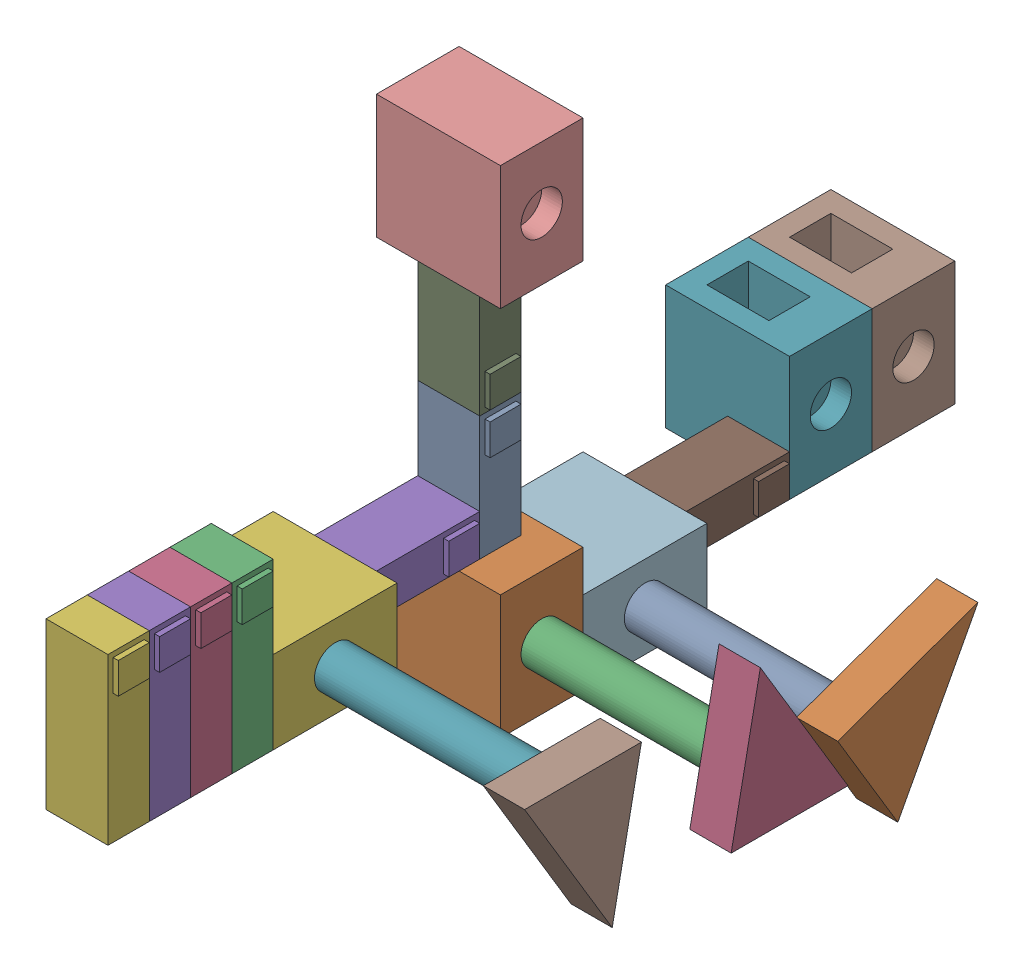
SolidWorks assembly Assem3, configuration Default. Lengths in mm.
Overall size (254 353.32 546.1).
27 component instances, 4 part files, 39 mates.
Components (placement in the parent):
- Assem1-1: Assem1 [Default] at origin size (76.2 152.4 50.8)
  - Part1-1: Part1 [Default] at (12.7 50.8 -12.7) size (41.27 101.6 25.4)
  - Part2-1: Part2 [Default] at origin size (76.2 76.2 50.8)
- Assem2-1: Assem2 [Default] at (228.6 20.1395 -61.321) x (0 0 1) z (0 -1 0) size (125.72 165.1 125.72)
  - Part3-1: Part3 [Default] at (35.921 12.7 -17.9605) x (0.684961 0 -0.72858) z (0.72858 0 0.684961) size (25.4 152.4 25.4)
  - Part4-1: Part4 [Default] x (0.707107 0 -0.707107) z (0.707107 0 0.707107) size (101.6 25.4 76.2)
- Assem1-2: Assem1 [Default] at (0 114.3 139.7) x (1 0 0) z (0 1 0) size (76.2 152.4 50.8)
  - Part1-1: Part1 [Default] at (12.7 50.8 -12.7) size (41.27 101.6 25.4)
  - Part2-1: Part2 [Default] at origin size (76.2 76.2 50.8)
- Assem2-2: Assem2 [Default] at (228.6 106.8605 137.521) x (0 0 -1) z (0 1 0) size (125.72 165.1 125.72)
  - Part3-1: Part3 [Default] at (35.921 12.7 -17.9605) x (0.684961 0 -0.72858) z (0.72858 0 0.684961) size (25.4 152.4 25.4)
  - Part4-1: Part4 [Default] x (0.707107 0 -0.707107) z (0.707107 0 0.707107) size (101.6 25.4 76.2)
- Assem1-3: Assem1 [Default] at (0 304.8 -50.8) x (1 0 0) z (0 0 -1) size (76.2 152.4 50.8)
  - Part1-1: Part1 [Default] at (12.7 50.8 -12.7) size (41.27 101.6 25.4)
  - Part2-1: Part2 [Default] at origin size (76.2 76.2 50.8)
- Assem1-4: Assem1 [Default] at (0 50.8 -50.8) x (1 0 0) z (0 1 0) size (76.2 152.4 50.8)
  - Part1-1: Part1 [Default] at (12.7 50.8 -12.7) size (41.27 101.6 25.4)
  - Part2-1: Part2 [Default] at origin size (76.2 76.2 50.8)
- Assem2-3: Assem2 [Default] at (228.6 -14.6426 -91.9802) x (0 0.857493 0.514496) z (0 -0.514496 0.857493) size (125.72 165.1 125.72)
  - Part3-1: Part3 [Default] at (35.921 12.7 -17.9605) x (0.684961 0 -0.72858) z (0.72858 0 0.684961) size (25.4 152.4 25.4)
  - Part4-1: Part4 [Default] x (0.707107 0 -0.707107) z (0.707107 0 0.707107) size (101.6 25.4 76.2)
- Part1-1: Part1 [Default] at (38.1 63.5 165.1) size (41.27 101.6 25.4)
- Part1-2: Part1 [Default] at (38.1 63.5 190.5) size (41.27 101.6 25.4)
- Part1-3: Part1 [Default] at (38.1 63.5 215.9) size (41.27 101.6 25.4)
- Part1-4: Part1 [Default] at (38.1 63.5 241.3) size (41.27 101.6 25.4)
- Part2-1: Part2 [Default] at (-25.4 12.7 -203.2) size (76.2 76.2 50.8)
- Part2-2: Part2 [Default] at (-25.4 12.7 -254) size (76.2 76.2 50.8)
Mates (geometry in assembly coordinates):
- Coincident1: coincident anti-aligned: plane of Assem1-1/Part2-1 through (63.5 38.1 -25.4) normal (1 0 0); plane of Assem2-1/Part3-1 through (63.5 38.1 -25.4) normal (-1 0 0)
- Concentric1: concentric aligned: cylinder of Assem1-1/Part2-1 through (63.5 38.1 -25.4) axis (1 0 0) radius 12.7; cylinder of Assem2-1/Part3-1 through (63.5 38.1 -25.4) axis (1 0 0) radius 12.7
- Coincident2: coincident: point of Assem1-1/Part2-1
- Coincident4: coincident aligned: plane of Assem1-1 through (0 0 0) normal (0 1 0)
- Parallel1: parallel anti-aligned: plane of Assem2-1 through (228.6 20.1395 -61.321) normal (0 -1 0)
- Coincident6: coincident aligned: plane of Assem1-1 through (0 0 0) normal (0 0 1)
- Coincident7: coincident aligned: plane of Assem1-1/Part1-1 through (50.8 152.4 -12.7) normal (1 0 0); plane of Assem1-2/Part1-1 through (50.8 101.6 -12.7) normal (1 0 0)
- Coincident8: coincident anti-aligned: plane of Assem1-1/Part1-1 through (12.7 152.4 -12.7) normal (0 0 1); plane of Assem1-2/Part1-1 through (12.7 101.6 -12.7) normal (0 0 -1)
- Coincident9: coincident anti-aligned: plane of Assem1-1/Part2-1 through (0 76.2 0) normal (0 1 0); plane of Assem1-2/Part1-1 through (12.7 76.2 -12.7) normal (0 -1 0)
- Concentric2: concentric aligned: cylinder of Assem1-2/Part2-1 through (63.5 88.9 101.6) axis (1 0 0) radius 12.7; cylinder of Assem2-2/Part3-1 through (63.5 88.9 101.6) axis (1 0 0) radius 12.7
- Coincident10: coincident anti-aligned: plane of Assem1-2/Part2-1 through (63.5 88.9 101.6) normal (1 0 0); plane of Assem2-2/Part3-1 through (63.5 88.9 101.6) normal (-1 0 0)
- Parallel2: parallel anti-aligned: plane of Assem2-1/Part4-1 through (203.2 20.1395 10.521) normal (0 0.196116 0.980581); plane of Assem2-2/Part4-1 through (203.2 106.8605 65.679) normal (0 -0.196116 -0.980581)
- Coincident11: coincident anti-aligned: plane of Assem1-1/Part1-1 through (12.7 152.4 -12.7) normal (0 1 0); plane of Assem1-3/Part1-1 through (12.7 152.4 -38.1) normal (0 -1 0)
- Coincident12: coincident aligned: plane of Assem1-1/Part1-1 through (12.7 152.4 -12.7) normal (-1 0 0); plane of Assem1-3/Part1-1 through (12.7 152.4 -38.1) normal (-1 0 0)
- Coincident14: coincident aligned: plane of Assem1-1/Part1-1 through (12.7 152.4 -12.7) normal (0 0 1); plane of Assem1-3/Part1-1 through (12.7 152.4 -12.7) normal (0 0 1)
- Coincident16: coincident anti-aligned: plane of Assem1-1/Part2-1 through (0 76.2 -50.8) normal (0 0 -1); plane of Assem1-4/Part2-1 through (0 50.8 -50.8) normal (0 0 1)
- Coincident18: coincident aligned: plane of Assem1-1/Part2-1 through (76.2 76.2 0) normal (1 0 0); plane of Assem1-4/Part2-1 through (76.2 50.8 -127) normal (1 0 0)
- Coincident19: coincident aligned: plane of Assem1-1/Part2-1 through (0 0 0) normal (0 -1 0); plane of Assem1-4/Part2-1 through (0 0 -127) normal (0 -1 0)
- Coincident20: coincident anti-aligned: plane of Assem1-4/Part2-1 through (63.5 25.4 -88.9) normal (1 0 0); plane of Assem2-3/Part3-1 through (63.5 25.4 -88.9) normal (-1 0 0)
- Concentric3: concentric aligned: cylinder of Assem1-4/Part2-1 through (63.5 25.4 -88.9) axis (1 0 0) radius 12.7; cylinder of Assem2-3/Part3-1 through (63.5 25.4 -88.9) axis (1 0 0) radius 12.7
- Parallel3: parallel anti-aligned: plane of Assem2-1/Part4-1 through (203.2 109.942 -7.4395) normal (0 0.514496 -0.857493); plane of Assem2-3/Part4-1 through (203.2 -14.6426 -91.9802) normal (0 -0.514496 0.857493)
- Coincident21: coincident anti-aligned: plane of Assem1-2/Part2-1 through (0 114.3 139.7) normal (0 0 1); plane of Part1-1 through (38.1 165.1 139.7) normal (0 0 -1)
- Coincident22: coincident anti-aligned: plane of Part1-1 through (38.1 165.1 165.1) normal (0 0 1); plane of Part1-2 through (38.1 165.1 165.1) normal (0 0 -1)
- Coincident23: coincident anti-aligned: plane of Part1-2 through (38.1 165.1 190.5) normal (0 0 1); plane of Part1-3 through (38.1 165.1 190.5) normal (0 0 -1)
- Coincident24: coincident anti-aligned: plane of Part1-3 through (38.1 165.1 215.9) normal (0 0 1); plane of Part1-4 through (38.1 165.1 215.9) normal (0 0 -1)
- Coincident25: coincident aligned: plane of Part1-1 through (38.1 63.5 165.1) normal (0 -1 0); plane of Part1-2 through (38.1 63.5 190.5) normal (0 -1 0)
- Coincident26: coincident aligned: plane of Part1-2 through (38.1 63.5 190.5) normal (0 -1 0); plane of Part1-3 through (38.1 63.5 215.9) normal (0 -1 0)
- Coincident27: coincident aligned: plane of Part1-3 through (38.1 63.5 215.9) normal (0 -1 0); plane of Part1-4 through (38.1 63.5 241.3) normal (0 -1 0)
- Coincident28: coincident aligned: plane of Part1-3 through (76.2 165.1 215.9) normal (1 0 0); plane of Part1-4 through (76.2 165.1 241.3) normal (1 0 0)
- Coincident29: coincident aligned: plane of Part1-2 through (76.2 165.1 190.5) normal (1 0 0); plane of Part1-3 through (76.2 165.1 215.9) normal (1 0 0)
- Coincident30: coincident aligned: plane of Part1-1 through (76.2 165.1 165.1) normal (1 0 0); plane of Part1-2 through (76.2 165.1 190.5) normal (1 0 0)
- Coincident31: coincident aligned: plane of Assem1-2/Part2-1 through (76.2 114.3 63.5) normal (1 0 0); plane of Part1-1 through (76.2 165.1 165.1) normal (1 0 0)
- Coincident32: coincident aligned: plane of Assem1-2/Part2-1 through (0 63.5 63.5) normal (0 -1 0); plane of Part1-1 through (38.1 63.5 165.1) normal (0 -1 0)
- Coincident33: coincident anti-aligned: plane of Assem1-4/Part1-1 through (12.7 38.1 -203.2) normal (0 0 -1); plane of Part2-1 through (-25.4 88.9 -203.2) normal (0 0 1)
- Coincident34: coincident aligned: plane of Assem1-4/Part1-1 through (12.7 12.7 -203.2) normal (0 -1 0); plane of Part2-1 through (-25.4 12.7 -203.2) normal (0 -1 0)
- Coincident35: coincident: line of Assem1-4/Part1-1 through (50.8 38.1 -203.2) axis (0 0 1); plane of Part2-1 through (50.8 88.9 -203.2) normal (1 0 0)
- Coincident36: coincident: plane of Part2-1 through (-25.4 12.7 -203.2) normal (0 -1 0); plane of Part2-2 through (-80.919 12.7 -254) normal (0 -1 0)
- Coincident37: coincident: plane of Part2-1 through (-25.4 88.9 -254) normal (0 0 -1); plane of Part2-2 through (-25.4 88.9 -254) normal (0 0 1)
- Coincident38: coincident aligned: plane of Part2-1 through (50.8 88.9 -203.2) normal (1 0 0); plane of Part2-2 through (50.8 88.9 -254) normal (1 0 0)
